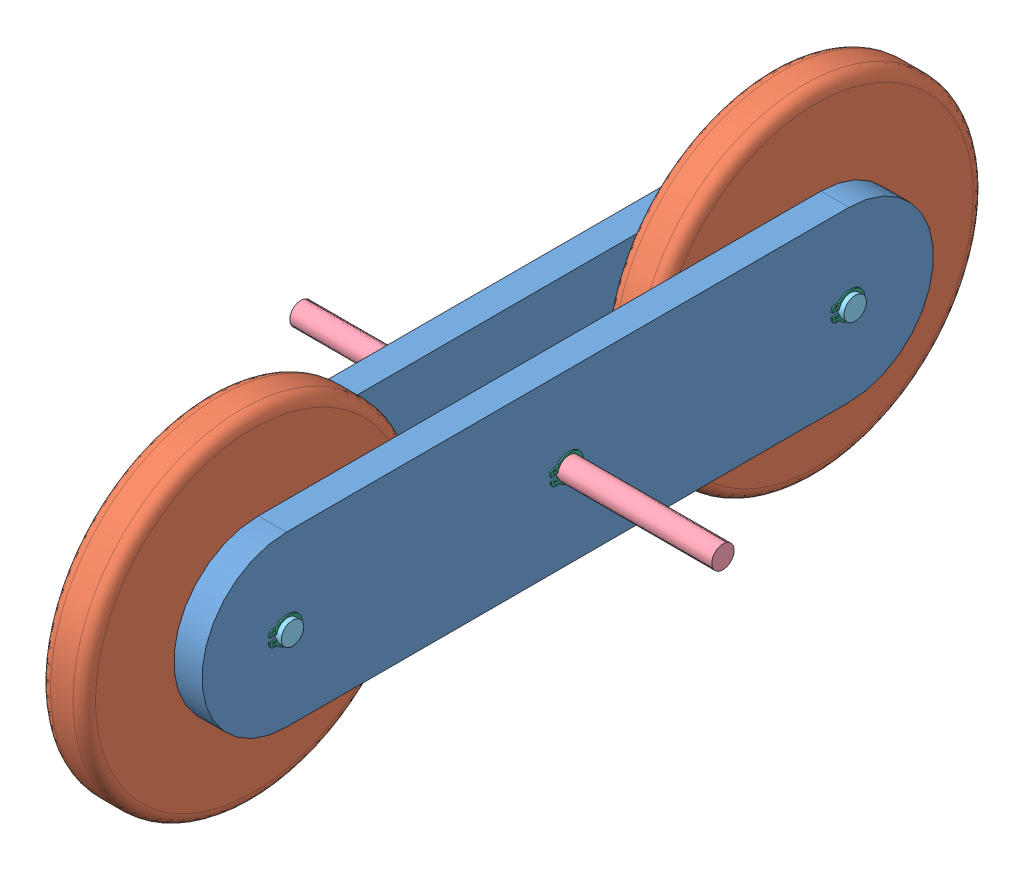
SolidWorks assembly Balancer, configuration Default. Lengths in mm.
Overall size (75 60.41 160.21).
17 component instances, 6 part files, 33 mates.
Components (placement in the parent):
- Balancer-lateral-1: Balancer-lateral [Default] at (57.5274 93.4575 114.567) size (5 30 130)
- Balancer-lateral-2: Balancer-lateral [Default] at (42.6994 93.4575 114.567) size (5 30 130)
- Balancer-Wheel-1: Balancer-Wheel [Default] at (48.6134 93.4575 164.567) x (1 0 0) z (0 -0.006923 0.999976) size (8 60 60)
- Balancer-Wheel-2: Balancer-Wheel [Default] at (48.6134 93.4575 64.567) size (8 60 60)
- Bearing-4mm-1: Bearing-4mm [Default] at (57.5275 93.4575 164.567) size (3.17 9.12 9.12)
- Bearing-4mm-2: Bearing-4mm [Default] at (47.6994 93.4575 164.567) x (-1 0 0) z (0 0 -1) size (3.17 9.12 9.12)
- Bearing-4mm-3: Bearing-4mm [Default] at (57.5275 93.4575 64.567) size (3.17 9.12 9.12)
- Bearing-4mm-4: Bearing-4mm [Default] at (47.6994 93.4575 64.567) x (-1 0 0) z (0 0 -1) size (3.17 9.12 9.12)
- Shaft-4mm-1: Shaft-4mm [Default] at (15.1134 93.4575 114.567) x (1 0 0) z (0 0.936019 -0.351949) size (75 4 4)
- Balancer-Shaft-4mm-1: Balancer-Shaft-4mm [Default] at (41.6134 93.4575 164.567) size (22 4 4)
- Balancer-Shaft-4mm-2: Balancer-Shaft-4mm [Default] at (41.6134 93.4575 64.567) size (22 4 4)
- msh_4-1: msh_4 [Default] at (62.6524 93.4575 164.567) x (0 1 0) z (0 0 1) size (4.59 0.25 5.77)
- msh_4-2: msh_4 [Default] at (42.5744 93.4575 164.567) x (0 0.77366 0.633601) z (0 -0.633601 0.77366) size (4.59 0.25 5.77)
- msh_4-3: msh_4 [Default] at (62.6524 93.4575 114.567) x (0 0.995776 0.091812) z (0 -0.091812 0.995776) size (4.59 0.25 5.77)
- msh_4-4: msh_4 [Default] at (42.5744 93.4575 114.567) x (0 1 0) z (0 0 1) size (4.59 0.25 5.77)
- msh_4-5: msh_4 [Default] at (62.6524 93.4575 64.567) x (0 1 0) z (0 0 1) size (4.59 0.25 5.77)
- msh_4-6: msh_4 [Default] at (42.5744 93.4575 64.567) x (0 1 0) z (0 0 1) size (4.59 0.25 5.77)
Mates (geometry in assembly coordinates):
- Coincidente10: coincident anti-aligned: plane of Balancer-Wheel-1 through (56.6134 93.4575 164.567) normal (1 0 0); plane of Bearing-4mm-1 through (56.6134 98.017 164.567) normal (-1 0 0)
- Concentrico5: concentric aligned: circle of Balancer-Wheel-1; circle of Bearing-4mm-1
- Coincidente11: coincident anti-aligned: plane of Balancer-Wheel-1 through (48.6134 93.4575 164.567) normal (-1 0 0); plane of Bearing-4mm-2 through (48.6134 98.017 164.567) normal (1 0 0)
- Concentrico6: concentric anti-aligned: circle of Balancer-Wheel-1; circle of Bearing-4mm-2
- Coincidente12: coincident anti-aligned: plane of Balancer-lateral-1 through (57.5274 93.4575 164.567) normal (-1 0 0); plane of Bearing-4mm-1 through (57.5274 96.7909 164.567) normal (1 0 0)
- Concentrico7: concentric aligned: circle of Balancer-lateral-1; circle of Bearing-4mm-1
- Coincidente13: coincident anti-aligned: plane of Balancer-lateral-2 through (47.6994 93.4575 164.567) normal (1 0 0); plane of Bearing-4mm-2 through (47.6994 96.7909 164.567) normal (-1 0 0)
- Concentrico8: concentric aligned: circle of Balancer-lateral-1; circle of Balancer-lateral-2
- Coincidente15: coincident anti-aligned: plane of Balancer-Wheel-2 through (56.6134 93.4575 64.567) normal (1 0 0); plane of Bearing-4mm-3 through (56.6134 98.017 64.567) normal (-1 0 0)
- Concentrico9: concentric aligned: circle of Balancer-Wheel-2; circle of Bearing-4mm-3
- Coincidente16: coincident anti-aligned: plane of Balancer-Wheel-2 through (48.6134 93.4575 64.567) normal (-1 0 0); plane of Bearing-4mm-4 through (48.6134 98.017 64.567) normal (1 0 0)
- Concentrico10: concentric anti-aligned: circle of Balancer-Wheel-2; circle of Bearing-4mm-4
- Coincidente17: coincident anti-aligned: plane of Balancer-lateral-2 through (47.6994 93.4575 164.567) normal (1 0 0); plane of Bearing-4mm-4 through (47.6994 96.7909 64.567) normal (-1 0 0)
- Concentrico11: concentric aligned: circle of Balancer-lateral-1; circle of Bearing-4mm-3
- Concentrico12: concentric aligned: circle of Balancer-lateral-1; circle of Balancer-lateral-2
- Concentrico13: concentric aligned: circle of Balancer-lateral-2; circle of Shaft-4mm-1
- Larghezza1: width anti-aligned: plane of Shaft-4mm-1 through (90.1134 93.4575 114.567) normal (1 0 0); plane of Shaft-4mm-1 through (15.1134 93.4575 114.567) normal (-1 0 0); plane of Balancer-lateral-2 through (42.6994 93.4575 164.567) normal (-1 0 0); plane of Balancer-lateral-1 through (62.5274 93.4575 164.567) normal (1 0 0)
- Concentrico15: concentric aligned: circle of Balancer-lateral-1; circle of Balancer-Shaft-4mm-1
- Larghezza2: width anti-aligned: plane of Balancer-Shaft-4mm-1 through (41.6134 93.4575 164.567) normal (-1 0 0); plane of Balancer-Shaft-4mm-1 through (63.6134 93.4575 164.567) normal (1 0 0); plane of Balancer-lateral-1 through (62.5274 93.4575 164.567) normal (1 0 0); plane of Balancer-lateral-2 through (42.6994 93.4575 164.567) normal (-1 0 0)
- Concentrico16: concentric aligned: circle of Balancer-lateral-1; circle of Balancer-Shaft-4mm-2
- Larghezza3: width aligned: plane of Balancer-Shaft-4mm-2 through (63.6134 93.4575 64.567) normal (1 0 0); plane of Balancer-Shaft-4mm-2 through (41.6134 93.4575 64.567) normal (-1 0 0); plane of Balancer-lateral-1 through (62.5274 93.4575 164.567) normal (1 0 0); plane of Balancer-lateral-2 through (42.6994 93.4575 164.567) normal (-1 0 0)
- Concentrico17: concentric aligned: circle of Balancer-Shaft-4mm-1; circle of msh_4-1
- Coincidente23: coincident anti-aligned: plane of Balancer-lateral-1 through (62.5274 93.4575 164.567) normal (1 0 0); plane of msh_4-1 through (62.5274 93.0075 167.7352) normal (-1 0 0)
- Concentrico18: concentric aligned: circle of Balancer-Shaft-4mm-1; circle of msh_4-2
- Coincidente24: coincident anti-aligned: plane of Balancer-lateral-2 through (42.6994 93.4575 164.567) normal (-1 0 0); plane of msh_4-2 through (42.6994 91.102 166.733) normal (1 0 0)
- Concentrico19: concentric aligned: circle of Balancer-lateral-1; circle of msh_4-3
- Coincidente25: coincident anti-aligned: plane of Balancer-lateral-1 through (62.5274 93.4575 164.567) normal (1 0 0); plane of msh_4-3 through (62.5274 92.7186 117.6805) normal (-1 0 0)
- Coincidente26: coincident anti-aligned: plane of Balancer-lateral-2 through (42.6994 93.4575 164.567) normal (-1 0 0); plane of msh_4-4 through (42.6994 93.0075 117.7352) normal (1 0 0)
- Concentrico20: concentric aligned: circle of Balancer-lateral-2; circle of msh_4-4
- Coincidente27: coincident anti-aligned: plane of Balancer-lateral-1 through (62.5274 93.4575 164.567) normal (1 0 0); plane of msh_4-5 through (62.5274 93.0075 67.7352) normal (-1 0 0)
- Concentrico21: concentric aligned: circle of Balancer-lateral-1; circle of msh_4-5
- Coincidente28: coincident anti-aligned: plane of Balancer-lateral-2 through (42.6994 93.4575 164.567) normal (-1 0 0); plane of msh_4-6 through (42.6994 93.0075 67.7352) normal (1 0 0)
- Concentrico22: concentric aligned: circle of Balancer-lateral-2; circle of msh_4-6
